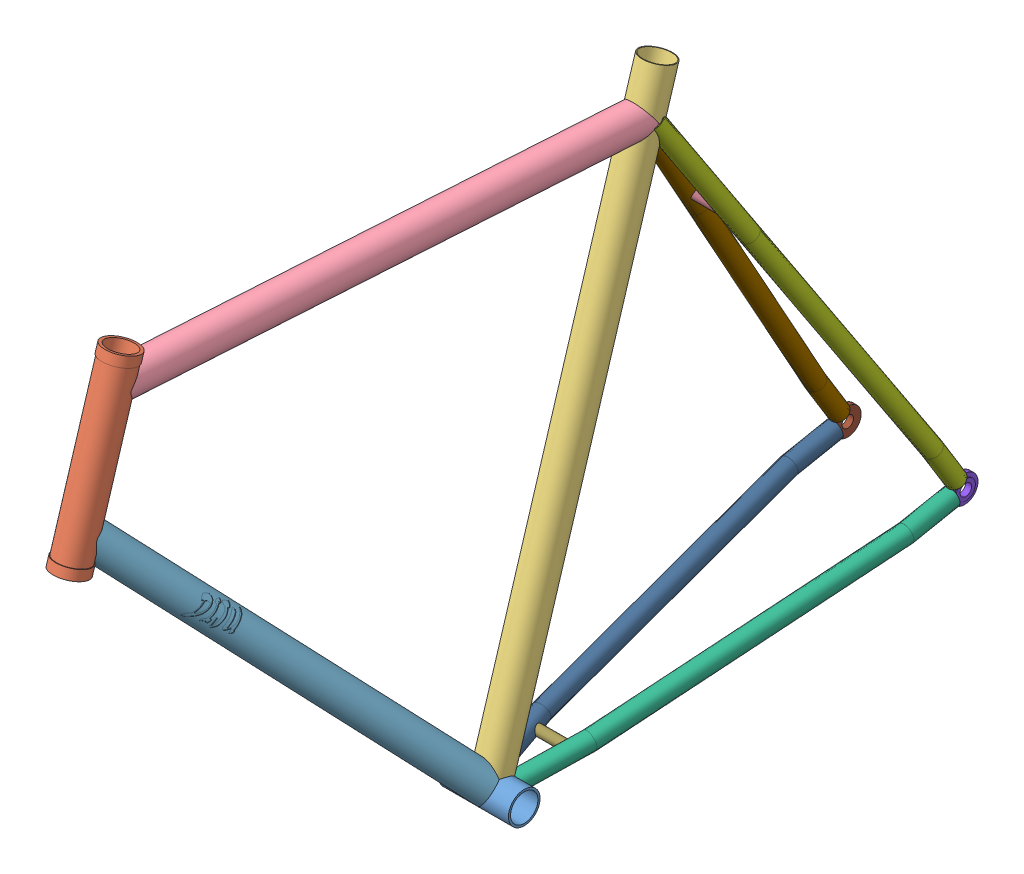
SolidWorks assembly cadre, configuration Défaut. Lengths in mm.
Overall size (140 613.27 908.21).
13 component instances, 13 part files, 67 mates.
Components (placement in the parent):
- tube pedalier^cadre-1: tube pedalier^cadre [Défaut] at origin size (73 33 33) (virtual)
- trou pour fourche^cadre-2: trou pour fourche^cadre [Défaut] at (0 502.9172 411.5258) x (0.998411 0.016475 0.053886) z (0 -0.956305 0.292372) size (35 35 185) (virtual)
- tube de selle^cadre-1: tube de selle^cadre [Défaut] at (0 573.7829 -175.423) x (1 0 0) z (0 0.956305 -0.292372) size (32.9 32.9 600.3) (virtual)
- tube de tete^cadre-1: tube de tete^cadre [Défaut] at (0 561.2509 393.6914) x (1 0 0) z (0 0.060491 0.998169) size (32.9 32.9 555.16) (virtual)
- tube du bas^cadre-3: tube du bas^cadre [Défaut] at (0 447.1547 428.5741) x (-1 0 0) z (0 -0.721947 -0.691948) size (32.91 32.9 618.4) (virtual)
- tube arriere bas^cadre-2: tube arriere bas^cadre [Défaut] at origin size (67.83 98.35 411.57) (virtual)
- tube arriere haut^cadre-1: tube arriere haut^cadre [Défaut] at origin size (69.56 441.01 279.99) (virtual)
- encoche roue^cadre-7: encoche roue^cadre [Défaut] at (61 85.0139 -432.7378) x (0 -0.852467 -0.522781) z (-1 0 0) size (54 61.43 6.25) (virtual)
- Symétrietube arriere haut^cadre-2: Symétrietube arriere haut^cadre [Défaut] x (-1 0 0) z (0 0 -1) size (69.56 441.01 279.99) (virtual)
- Symétrietube arriere bas^cadre-3: Symétrietube arriere bas^cadre [Défaut] x (-1 0 0) z (0 0 -1) size (67.83 98.35 411.57) (virtual)
- Symétrieencoche roue^cadre-8: Symétrieencoche roue^cadre [Défaut] at (-61 85.0139 -432.7378) x (0 -0.852467 -0.522781) z (-1 0 0) size (54 61.43 6.25) (virtual)
- tube consolider 1^cadre-1: tube consolider 1^cadre [Défaut] x (0 0 -1) z (1 0 0) size (10 10 30.38) (virtual)
- tube consolider 2^cadre-1: tube consolider 2^cadre [Défaut] x (0 0 -1) z (1 0 0) size (10 10 34.39) (virtual)
Mates (geometry in assembly coordinates):
- Coaxiale2: concentric anti-aligned: cylinder of trou pour fourche^cadre-logo-2 through (0 581.8123 387.4052) axis (0 -0.956305 0.292372) radius 16.75
- Sur place1: in place: plane of tube de selle^cadre-1 through (0 573.7829 -175.423) normal (0 0.956305 -0.292372); moOrthogonalPlaneRef_w of tube de selle^cadre-1 through (0 573.7829 -175.423) normal (0 -0.292372 -0.956305); plane of tube de selle^cadre-1 through (0 573.7829 -175.423) normal (1 0 0); unknown of tube de selle^cadre-1
- Coïncidente10: coincident aligned: 
- Coïncidente11: coincident aligned: plane of tube de selle^cadre-logo-1 through (0 573.7829 -175.423) normal (0 -0.292372 -0.956305)
- Coïncidente12: coincident anti-aligned: plane of tube de selle^cadre-logo-1 through (0 573.7829 -175.423) normal (1 0 0)
- Sur place2: in place: plane of tube de tete^cadre-1 through (0 561.2509 393.6914) normal (0 0.060491 0.998169); plane of tube de tete^cadre-1 through (0 561.2509 393.6914) normal (0 0.998169 -0.060491); plane of tube de tete^cadre-1 through (0 561.2509 393.6914) normal (1 0 0); unknown of tube de tete^cadre-1
- Coïncidente13: coincident aligned: 
- Coïncidente14: coincident aligned: plane of tube de tete^cadre-logo-1 through (0 561.2509 393.6914) normal (0 0.998169 -0.060491)
- Coïncidente15: coincident anti-aligned: plane of tube de tete^cadre-logo-1 through (0 561.2509 393.6914) normal (1 0 0)
- Sur place4: in place: plane of tube du bas^cadre-3 through (0 447.1547 428.5741) normal (0 -0.721947 -0.691948); plane of tube du bas^cadre-3 through (0 447.1547 428.5741) normal (0 0.691948 -0.721947); plane of tube du bas^cadre-3 through (0 447.1547 428.5741) normal (-1 0 0); unknown of tube du bas^cadre-3
- Coïncidente4: coincident aligned: 
- Coïncidente5: coincident aligned: plane of tube du bas^cadre-logo-3 through (0 447.1547 428.5741) normal (0 0.691948 -0.721947)
- Coïncidente6: coincident anti-aligned: plane of tube du bas^cadre-logo-3 through (0 447.1547 428.5741) normal (-1 0 0)
- Sur place5: in place: plane of ? through (0 0 0) normal (0 0.981244 0.192771); plane of ? through (0 0 0) normal (0 0.192771 -0.981244); plane of ? through (0 0 0) normal (1 0 0); unknown of ?
- Coïncidente7: coincident aligned: 
- Coïncidente8: coincident aligned: plane of chain stay tube^Assemblage1-1 through (0 0 0) normal (0 0.192771 -0.981244)
- Coïncidente9: coincident anti-aligned: plane of chain stay tube^Assemblage1-1 through (0 0 0) normal (-1 0 0)
- Sur place6: in place: plane of ? through (0 248.264 -356.0781) normal (0 -0.57193 0.820303); plane of ? through (0 248.264 -356.0781) normal (0 0.820303 0.57193); plane of ? through (0 248.264 -356.0781) normal (1 0 0); unknown of ?
- Coïncidente1: coincident aligned: 
- Coïncidente2: coincident aligned: plane of Pièce1^Assemblage1-1 through (0 248.264 -356.0781) normal (0 0.820303 0.57193)
- Coïncidente3: coincident anti-aligned: plane of Pièce1^Assemblage1-1 through (0 248.264 -356.0781) normal (-1 0 0)
- Sur place7: in place: plane of ? through (0 248.264 -356.0781) normal (0 0.57193 -0.820303); plane of ? through (0 248.264 -356.0781) normal (0 0.820303 0.57193); plane of ? through (0 248.264 -356.0781) normal (-1 0 0); unknown of ?
- Coïncidente1: coincident aligned: 
- Coïncidente2: coincident aligned: plane of thin tube^Assemblage1-2 through (0 248.264 -356.0781) normal (0 0.820303 0.57193)
- Coïncidente3: coincident anti-aligned: plane of thin tube^Assemblage1-2 through (0 248.264 -356.0781) normal (-1 0 0)
- Coïncidente4: coincident: unknown of rear dropout-1
- Coïncidente6: coincident: unknown of rer droppout good-1
- Parallèle2: parallel anti-aligned: cylinder of chain stay tube^Assemblage1-1 through (67.5 91.4349 -465.4222) axis (0 -0.192771 0.981244) radius 11.15; line of rer droppout good-1 through (70 91.574 -424.6303) axis (0 0.192771 -0.981244)
- Sur place8: in place: plane of ? through (0 0 0) normal (1 0 0); plane of ? through (0 0 0) normal (0 1 0); plane of ? through (0 0 0) normal (0 0 -1); unknown of ?
- Coïncidente9: coincident aligned: 
- Coïncidente10: coincident aligned: plane of Pièce1^Assemblage1-1 through (0 0 0) normal (0 1 0)
- Coïncidente11: coincident anti-aligned: plane of Pièce1^Assemblage1-1 through (0 0 0) normal (0 0 -1)
- Sur place9: in place: plane of ? through (0 0 0) normal (1 0 0); plane of ? through (0 0 0) normal (0 1 0); plane of ? through (0 0 0) normal (0 0 -1); unknown of ?
- Coïncidente12: coincident aligned: 
- Coïncidente13: coincident aligned: plane of Pièce2^Assemblage1-1 through (0 0 0) normal (0 1 0)
- Coïncidente14: coincident anti-aligned: plane of Pièce2^Assemblage1-1 through (0 0 0) normal (0 0 -1)
- Sur place10: in place: plane of ? through (0 0 0) normal (-1 0 0); plane of ? through (0 0 0) normal (-1 0 0); plane of ? through (0 0 0) normal (-1 0 0); plane of ? through (0 0 0) normal (0 0.192771 -0.981244); plane of ? through (0 0 0) normal (-1 0 0); plane of ? through (0 0 0) normal (0 0.981244 0.192771); plane of ? through (0 0 0) normal (-1 0 0); unknown of ?
- Coïncidente15: coincident aligned: plane of ?; plane of ?
- Coïncidente16: coincident aligned: moOrthogonalPlaneRef_w of chain stay tube^Assemblage1-1 through (0 0 0) axis (0.192771 -0.981244 0); plane of Pièce3^Assemblage1-1 through (0 0 0) normal (0 0.192771 -0.981244)
- Coïncidente17: coincident anti-aligned: moOrthogonalPlaneRef_w of chain stay tube^Assemblage1-1 through (0 0 0) axis (-0.981244 -0.192771 0); plane of Pièce3^Assemblage1-1 through (0 0 0) normal (0 0.981244 0.192771)
- Sur place11: in place: plane of ? through (0 0 0) normal (0 0.981244 0.192771); plane of ? through (0 0 0) normal (0 0.192771 -0.981244); plane of ? through (0 0 0) normal (1 0 0); unknown of ?
- Coïncidente18: coincident aligned: 
- Coïncidente19: coincident aligned: plane of Pièce4^Assemblage1-1 through (0 0 0) normal (0 0.192771 -0.981244)
- Coïncidente20: coincident anti-aligned: plane of Pièce4^Assemblage1-1 through (0 0 0) normal (1 0 0)
- Sur place12: in place: plane of ? through (0 248.264 -356.0781) normal (0 0.57193 -0.820303); plane of ? through (0 248.264 -356.0781) normal (0 0.820303 0.57193); plane of ? through (0 248.264 -356.0781) normal (-1 0 0); unknown of ?
- Coïncidente21: coincident aligned: 
- Coïncidente22: coincident aligned: plane of little tube 2^cadre-1 through (0 0 -356.0781) normal (0 1 0)
- Coïncidente23: coincident anti-aligned: plane of little tube 2^cadre-1 through (0 0 -356.0781) normal (1 0 0)
- Parallèle4: parallel aligned: plane of encoche roue^cadre-logo-7 through (63.5 85.0139 -432.7378) normal (1 0 0)
- Parallèle6: parallel anti-aligned: cylinder of tube arriere haut^cadre-logo-1 through (61 85.0139 -432.7378) axis (0 0.852467 0.522781) radius 9; line of encoche roue^cadre-logo-7 through (63.5 122.772 -417.7938) axis (0 -0.852467 -0.522781)
- Sur place13: in place: plane of ? through (0 12.9269 -65.8007) normal (0 0.192771 -0.981244); plane of ? through (0 12.9269 -65.8007) normal (0 0.981244 0.192771); plane of ? through (0 12.9269 -65.8007) normal (-1 0 0); unknown of ?
- Coïncidente9: coincident aligned: 
- Coïncidente10: coincident aligned: plane of Pièce6^cadre-1 through (0 0 -65.8007) normal (0 1 0)
- Coïncidente11: coincident anti-aligned: plane of Pièce6^cadre-1 through (0 0 -65.8007) normal (1 0 0)
- Sur place14: in place: plane of ? through (0 0 0) normal (1 0 0); plane of ? through (0 0 0) normal (0 1 0); plane of ? through (0 0 0) normal (0 0 -1); unknown of ?
- Coïncidente12: coincident aligned: 
- Coïncidente13: coincident aligned: plane of tube consolider 1^cadre-logo-1 through (0 0 0) normal (0 1 0)
- Coïncidente14: coincident anti-aligned: plane of tube consolider 1^cadre-logo-1 through (0 0 0) normal (0 0 -1)
- Sur place15: in place: plane of ? through (0 0 0) normal (1 0 0); plane of ? through (0 0 0) normal (0 1 0); plane of ? through (0 0 0) normal (0 0 -1); unknown of ?
- Coïncidente15: coincident aligned: 
- Coïncidente16: coincident aligned: plane of tube consolider 2^cadre-logo-1 through (0 0 0) normal (0 1 0)
- Coïncidente17: coincident anti-aligned: plane of tube consolider 2^cadre-logo-1 through (0 0 0) normal (0 0 -1)
- Coïncidente7: coincident: unknown of encoche roue^cadre-logo-7
- Sur place16: in place: plane of ? through (0 0 0) normal (0 1 0); plane of ? through (0 0 0) normal (0 0 -1); plane of ? through (0 0 0) normal (1 0 0); unknown of ?
- Coïncidente8: coincident aligned: 
- Coïncidente9: coincident aligned: plane of Pièce1^cadre-logo-1 through (0 0 0) normal (0 0 -1)
- Coïncidente10: coincident anti-aligned: plane of Pièce1^cadre-logo-1 through (0 0 0) normal (1 0 0)
